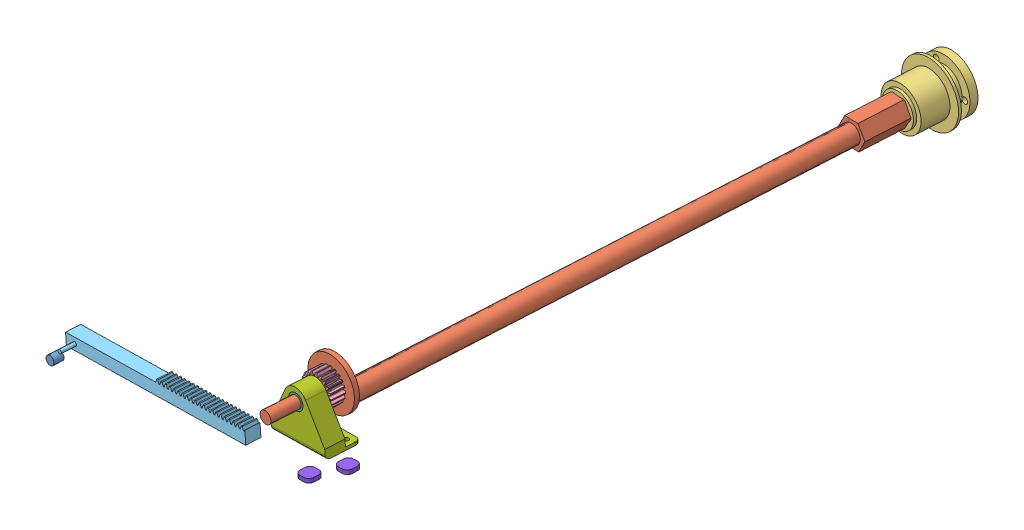
SolidWorks assembly Assem1, configuration Default. Lengths in mm.
Overall size (373.66 154.69 682.45).
9 component instances, 8 part files, 20 mates.
Components (placement in the parent):
- Part2^Assem1-1: Part2^Assem1 [Default] at (-41.7791 25.9211 465.3465) x (0.998298 -0.000084 0.058321) z (-0.058321 -0.001438 0.998297) size (8.91 8.91 10) (virtual)
- adapterplate(unfinished)-1: adapterplate(unfinished) [Default] at (143.4268 366.7073 466.6403) x (0.998258 0.008894 0.058332) z (-0.058321 -0.001438 0.998297) size (52 55.36 679.6)
- Quick Release (Non-Functional)-1: Quick Release (Non-Functional) [Default] at (179.4187 351.1168 -146.9281) x (-0.900526 -0.431532 -0.053231) z (-0.430873 0.902097 -0.023873) size (63.5 54.37 63.5)
- KHK-US_SSA1_5-20J12.stp-1: KHK-US_SSA1_5-20J12.stp [Default] at (142.9893 366.6966 474.1275) x (0.058321 0.001438 -0.998297) z (0.008962 -0.999959 -0.000917) size (15 33 33)
- KHK-US_SRAF1_5-1000.stp-1: KHK-US_SRAF1_5-1000.stp [Default] at (462.0664 313.1053 492.6911) x (-0.058321 -0.001438 0.998297) z (-0.995329 -0.076979 -0.058259) size (30.71 15 200)
- 6995N126_Iron-Copper High-Load Oil-Embedded Sleeve Bearing-1: 6995N126_Iron-Copper High-Load Oil-Embedded Sleeve Bearing [6995N126] at (141.9687 366.6714 491.5977) x (0.75906 0.649445 0.04528) z (-0.058321 -0.001438 0.998297) size (16 16 20)
- slider-1: slider [Default] at (142.5519 366.6858 481.6147) x (0.995329 0.076979 0.058259) z (-0.058321 -0.001438 0.998297) size (60 51.5 35)
- delrinshim-1: delrinshim [Default] at (169.7617 311.6976 475.6123) x (0.995329 0.076979 0.058259) z (0.058321 0.001438 -0.998297) size (15 4 15)
- delrinshim-2: delrinshim [Default] at (127.0479 281.3274 473.0732) x (-0.995329 -0.076979 -0.058259) z (-0.058321 -0.001438 0.998297) size (15 4 15)
Mates (geometry in assembly coordinates):
- Concentric6: concentric anti-aligned: cylinder of adapterplate(unfinished)-1 through (179.4187 351.1168 -146.9281) axis (-0.058321 -0.001438 0.998297) radius 9.525; cylinder of Quick Release (Non-Functional)-1 through (179.4187 351.1168 -146.9281) axis (0.058321 0.001438 -0.998297) radius 22.225
- Coincident6: coincident aligned: plane of adapterplate(unfinished)-1 through (179.4187 351.1168 -146.9281) normal (0.058321 0.001438 -0.998297); plane of Quick Release (Non-Functional)-1 through (179.4187 351.1168 -146.9281) normal (0.058321 0.001438 -0.998297)
- Concentric7: concentric aligned: cylinder of adapterplate(unfinished)-1 through (142.5519 366.6858 481.6147) axis (0.058321 0.001438 -0.998297) radius 6; cylinder of KHK-US_SSA1_5-20J12.stp-1 through (143.5142 366.7095 465.1428) axis (0.058321 0.001438 -0.998297) radius 6
- Coincident7: coincident anti-aligned: plane of adapterplate(unfinished)-1 through (143.4268 366.7073 466.6403) normal (-0.058321 -0.001438 0.998297); plane of KHK-US_SSA1_5-20J12.stp-1 through (143.4268 366.7073 466.6403) normal (0.058321 0.001438 -0.998297)
- Coincident10: coincident: plane of adapterplate(unfinished)-1 through (143.4268 366.7073 466.6403) normal (-0.058321 -0.001438 0.998297); plane of KHK-US_SRAF1_5-1000.stp-1 through (298.2656 315.6771 475.6126) normal (0.058321 0.001438 -0.998297)
- Distance1: distance = 28.5 mm: line of KHK-US_SRAF1_5-1000.stp-1 through (296.711 303.9755 490.5305) axis (-0.996606 0.058282 -0.058139); cylinder of adapterplate(unfinished)-1 through (128.2322 342.3765 480.7431) axis (0.058321 0.001438 -0.998297) radius 6
- Coincident12: coincident anti-aligned: plane of adapterplate(unfinished)-1 through (144.4794 374.4032 481.7384) normal (0.998258 0.008894 0.058332); plane of KHK-US_SSA1_5-20J12.stp-1 through (145.4408 374.527 465.2666) normal (-0.998258 -0.008894 -0.058332)
- Concentric8: concentric aligned: cylinder of adapterplate(unfinished)-1 through (142.5519 366.6858 481.6147) axis (0.058321 0.001438 -0.998297) radius 6; cylinder of 6995N126_Iron-Copper High-Load Oil-Embedded Sleeve Bearing-1 through (141.3855 366.657 501.5807) axis (0.058321 0.001438 -0.998297) radius 6
- Coincident13: coincident anti-aligned: plane of KHK-US_SSA1_5-20J12.stp-1 through (142.5519 366.6858 481.6147) normal (-0.058321 -0.001438 0.998297); plane of 6995N126_Iron-Copper High-Load Oil-Embedded Sleeve Bearing-1 through (142.5519 366.6858 481.6147) normal (0.058321 0.001438 -0.998297)
- Concentric9: concentric aligned: cylinder of 6995N126_Iron-Copper High-Load Oil-Embedded Sleeve Bearing-1 through (141.3855 366.657 501.5807) axis (0.058321 0.001438 -0.998297) radius 8; cylinder of slider-1 through (141.3855 366.657 501.5807) axis (0.058321 0.001438 -0.998297) radius 8
- Coincident14: coincident anti-aligned: plane of KHK-US_SSA1_5-20J12.stp-1 through (142.5519 366.6858 481.6147) normal (-0.058321 -0.001438 0.998297); plane of slider-1 through (142.5519 366.6858 481.6147) normal (0.058321 0.001438 -0.998297)
- Parallel1: parallel: plane of KHK-US_SRAF1_5-1000.stp-1 through (297.5858 303.997 475.5561) normal (-0.058099 -0.998299 -0.004832); plane of slider-1 through (154.7271 302.1647 502.2672) normal (-0.058099 -0.998299 -0.004832)
- Coincident21: coincident: plane of KHK-US_SRAF1_5-1000.stp-1 through (297.5858 303.997 475.5561) normal (-0.058099 -0.998299 -0.004832); plane of delrinshim-1 through (152.0747 312.4823 472.0759) normal (0.058099 0.998299 0.004832)
- Coincident22: coincident anti-aligned: plane of slider-1 through (142.5519 366.6858 481.6147) normal (0.058321 0.001438 -0.998297); plane of delrinshim-1 through (167.1437 307.5063 482.9661) normal (-0.058321 -0.001438 0.998297)
- Coincident23: coincident aligned: plane of slider-1 through (173.4379 340.551 503.4156) normal (0.995329 0.076979 0.058259); plane of delrinshim-1 through (177.6802 308.2904 473.5658) normal (0.995329 0.076979 0.058259)
- Coincident24: coincident: plane of KHK-US_SRAF1_5-1000.stp-1 through (297.5858 303.997 475.5561) normal (-0.058099 -0.998299 -0.004832); plane of delrinshim-2 through (101.9528 315.3892 474.1605) normal (0.058099 0.998299 0.004832)
- Coincident25: coincident anti-aligned: plane of slider-1 through (142.5519 366.6858 481.6147) normal (0.058321 0.001438 -0.998297); plane of delrinshim-2 through (129.4066 277.521 480.7183) normal (-0.058321 -0.001438 0.998297)
- Coincident26: coincident aligned: plane of slider-1 through (114.4875 325.9619 499.9506) normal (-0.995329 -0.076979 -0.058259); plane of delrinshim-2 through (119.7449 276.7584 475.1442) normal (-0.995329 -0.076979 -0.058259)
- Coincident27: coincident anti-aligned: plane of KHK-US_SRAF1_5-1000.stp-1 through (959.2609 345.7142 529.2974) normal (-0.058321 -0.001438 0.998297); plane of slider-1 through (142.5519 366.6858 481.6147) normal (0.058321 0.001438 -0.998297)
- Coincident28: coincident anti-aligned: plane of KHK-US_SRAF1_5-1000.stp-1 through (960.1357 345.7358 514.3229) normal (0.076932 -0.997032 0.003058); plane of delrinshim-2 through (124.4138 281.1314 475.4233) normal (-0.076932 0.997032 -0.003058)
